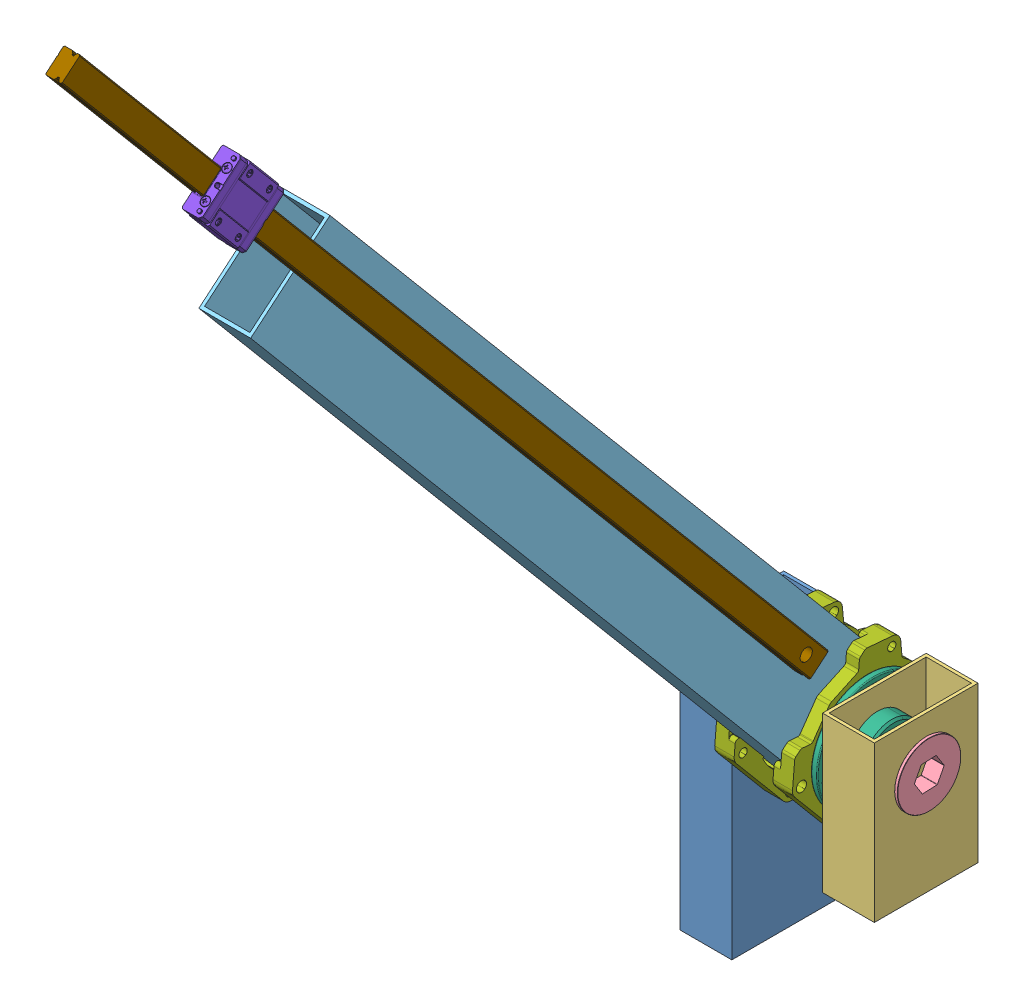
SolidWorks assembly Climber vsomething with rail, configuration Default. Lengths in mm.
Overall size (101.11 586.72 443.22).
12 component instances, 9 part files, 29 mates.
Components (placement in the parent):
- Climb Mount large-1: Climb Mount large [Default] at (52.6266 16.6141 118.8348) x (0 0 1) z (0 1 0) size (50.8 25.4 127)
- Climb axle-1: Climb axle [Default] at (124.4915 118.2141 118.8348) x (0 0.886216 -0.463271) z (-1 0 0) size (14.66 12.7 88.9)
- Climb Mount small-1: Climb Mount small [Default] at (122.4766 67.4141 118.8348) x (0 0 -1) z (0 1 0) size (50.8 25.4 76.2)
- am-2986 FR8ZZ Hex Bearing.step-1: am-2986 FR8ZZ Hex Bearing.step [Default] at (128.7732 118.2141 118.8348) x (0 0.886216 -0.463271) z (1 0 0) size (31.12 31.12 7.93)
- am-2986 FR8ZZ Hex Bearing.step-3: am-2986 FR8ZZ Hex Bearing.step [Default] at (46.3299 118.2141 118.8348) x (0 0 1) z (-1 0 0) size (31.12 31.12 7.93)
- Lower climb arm-1: Lower climb arm [Default] at (87.5516 99.754 101.3217) x (0 -0.643568 0.765389) z (-1 0 0) size (50.8 457.2 25.4)
- 1_2” Hex Bore Aluminum VersaHub (217-2592).step-1: 1_2” Hex Bore Aluminum VersaHub (217-2592).step [Default] at (55.8016 118.2141 118.8348) x (1 0 0) z (0 -0.643568 0.765389) size (12.7 55.88 55.88)
- 1_2” Hex Bore Aluminum VersaHub (217-2592).step-2: 1_2” Hex Bore Aluminum VersaHub (217-2592).step [Default] at (119.3016 118.2141 118.8348) x (-1 0 0) z (0 -0.341062 -0.940041) size (12.7 55.88 55.88)
- VersaBlock V2 (217-6111).step-1: VersaBlock V2 (217-6111).step [Default] at (71.6766 118.2141 118.8348) x (0 0.765389 0.643568) z (-1 0 0) size (61.04 66.67 9.53)
- VersaBlock V2 (217-6111).step-2: VersaBlock V2 (217-6111).step [Default] at (103.4266 118.2141 118.8348) x (0 -0.765389 -0.643568) z (1 0 0) size (61.04 66.67 9.53)
- 6709K115_Ball Bearing Carriage-1: 6709K115_Ball Bearing Carriage [6709K115] at (106.7516 504.278 431.2198) x (0 -0.643568 0.765389) z (0 0.765389 0.643568) size (27 10.16 34.7)
- 6709K173_Ball Bearing rail-1: 6709K173_Ball Bearing rail [6709K173] at (104.2516 381.3417 327.6783) x (0 0.643568 -0.765389) z (0 -0.765389 -0.643568) size (12 8.07 570)
Mates (geometry in assembly coordinates):
- Concentric1: concentric anti-aligned: cylinder of Climb Mount large-1 through (65.3266 118.2141 118.8348) axis (-1 0 0) radius 14.2875; cylinder of Climb Mount small-1 through (109.7766 118.2141 118.8348) axis (1 0 0) radius 14.2875
- Coincident1: coincident aligned: plane of Climb Mount large-1 through (52.6266 143.6141 118.8348) normal (0 1 0); plane of Climb Mount small-1 through (122.4766 143.6141 118.8348) normal (0 1 0)
- Coincident4: coincident anti-aligned: plane of Climb Mount small-1 through (135.1766 143.6141 93.4348) normal (1 0 0); plane of am-2986 FR8ZZ Hex Bearing.step-1 through (135.1766 130.5945 112.3629) normal (-1 0 0)
- Concentric3: concentric anti-aligned: cylinder of Climb Mount small-1 through (109.7766 118.2141 118.8348) axis (1 0 0) radius 14.2875; cylinder of am-2986 FR8ZZ Hex Bearing.step-1 through (136.7006 118.2141 118.8348) axis (-1 0 0) radius 14.2875
- Coincident6: coincident anti-aligned: plane of Climb Mount large-1 through (39.9266 143.6141 144.2348) normal (-1 0 0); plane of am-2986 FR8ZZ Hex Bearing.step-3 through (39.9266 118.2141 132.8048) normal (1 0 0)
- Concentric5: concentric anti-aligned: line of Climb Mount large-1 through (65.3266 118.2141 118.8348) axis (-1 0 0); axis of am-2986 FR8ZZ Hex Bearing.step-3 through (40.4346 118.2141 118.8348) axis (1 0 0)
- Coincident7: coincident anti-aligned: plane of Climb axle-1 through (35.5915 117.9068 126.1607) normal (0 0.463271 0.886216); plane of am-2986 FR8ZZ Hex Bearing.step-1 through (136.7006 117.9068 126.1607) normal (0 -0.463271 -0.886216)
- Coincident8: coincident anti-aligned: plane of Climb axle-1 through (35.5915 124.7121 115.4379) normal (0 0.53585 -0.844313); plane of am-2986 FR8ZZ Hex Bearing.step-1 through (136.7006 124.7121 115.4379) normal (0 -0.53585 0.844313)
- Coincident10: coincident anti-aligned: plane of Lower climb arm-1 through (74.8516 433.3431 415.0019) normal (-1 0 0); plane of VersaBlock V2 (217-6111).step-1 through (74.8516 118.2141 118.8348) normal (1 0 0)
- Coincident11: coincident anti-aligned: plane of Lower climb arm-1 through (74.8516 433.3431 415.0019) normal (0 -0.643568 0.765389); plane of VersaBlock V2 (217-6111).step-1 through (-4.6404 126.2065 156.7497) normal (0 0.643568 -0.765389)
- Coincident12: coincident anti-aligned: plane of Lower climb arm-1 through (74.8516 433.3431 415.0019) normal (0 -0.643568 0.765389); plane of VersaBlock V2 (217-6111).step-2 through (179.7436 79.49 117.4687) normal (0 0.643568 -0.765389)
- Coincident13: coincident anti-aligned: plane of Lower climb arm-1 through (100.2516 433.3431 415.0019) normal (1 0 0); plane of VersaBlock V2 (217-6111).step-2 through (100.2516 118.2141 118.8348) normal (-1 0 0)
- Parallel1: parallel anti-aligned: plane of Climb Mount small-1 through (109.7766 143.6141 93.4348) normal (-1 0 0); plane of Lower climb arm-1 through (100.2516 433.3431 415.0019) normal (1 0 0)
- Concentric6: concentric anti-aligned: cylinder of Lower climb arm-1 through (-356.9484 118.2141 118.8348) axis (1 0 0) radius 12.7; cylinder of VersaBlock V2 (217-6111).step-1 through (113.7106 118.2141 118.8348) axis (-1 0 0) radius 14.2748
- Concentric7: concentric aligned: cylinder of Lower climb arm-1 through (-356.9484 118.2141 118.8348) axis (1 0 0) radius 12.7; cylinder of VersaBlock V2 (217-6111).step-2 through (61.3926 118.2141 118.8348) axis (1 0 0) radius 14.2748
- Coincident16: coincident anti-aligned: plane of 1_2” Hex Bore Aluminum VersaHub (217-2592).step-2 through (106.6016 147.8694 108.0754) normal (-1 0 0); plane of VersaBlock V2 (217-6111).step-2 through (106.6016 114.0552 142.2813) normal (1 0 0)
- Concentric8: concentric anti-aligned: cylinder of 1_2” Hex Bore Aluminum VersaHub (217-2592).step-2 through (192.3949 99.9883 103.5098) axis (-1 0 0) radius 2.15; cylinder of VersaBlock V2 (217-6111).step-2 through (106.6016 99.9883 103.5098) axis (1 0 0) radius 2.4892
- Concentric9: concentric anti-aligned: cylinder of 1_2” Hex Bore Aluminum VersaHub (217-2592).step-2 through (192.3949 95.8294 126.9563) axis (-1 0 0) radius 2.15; cylinder of VersaBlock V2 (217-6111).step-2 through (106.6016 95.8294 126.9563) axis (1 0 0) radius 1.7272
- Coincident17: coincident anti-aligned: plane of 1_2” Hex Bore Aluminum VersaHub (217-2592).step-1 through (68.5016 142.3596 139.1373) normal (1 0 0); plane of VersaBlock V2 (217-6111).step-1 through (68.5016 95.8294 126.9563) normal (-1 0 0)
- Concentric10: concentric anti-aligned: cylinder of 1_2” Hex Bore Aluminum VersaHub (217-2592).step-1 through (-17.2918 99.9883 103.5098) axis (1 0 0) radius 2.15; cylinder of VersaBlock V2 (217-6111).step-1 through (68.5016 99.9883 103.5098) axis (-1 0 0) radius 2.4892
- Concentric11: concentric anti-aligned: cylinder of 1_2” Hex Bore Aluminum VersaHub (217-2592).step-1 through (-17.2918 95.8294 126.9563) axis (1 0 0) radius 2.15; cylinder of VersaBlock V2 (217-6111).step-1 through (68.5016 95.8294 126.9563) axis (-1 0 0) radius 1.7272
- Concentric12: concentric anti-aligned: cylinder of Climb Mount small-1 through (109.7766 118.2141 118.8348) axis (1 0 0) radius 14.2875; cylinder of 1_2” Hex Bore Aluminum VersaHub (217-2592).step-2 through (106.6016 118.2141 118.8348) axis (-1 0 0) radius 14.2949
- Coincident18: coincident anti-aligned: plane of Climb Mount small-1 through (109.7766 143.6141 93.4348) normal (-1 0 0); plane of 1_2” Hex Bore Aluminum VersaHub (217-2592).step-2 through (109.7766 131.6519 113.9593) normal (1 0 0)
- Coincident20: coincident anti-aligned: plane of Climb Mount large-1 through (65.3266 143.6141 144.2348) normal (1 0 0); plane of 1_2” Hex Bore Aluminum VersaHub (217-2592).step-1 through (65.3266 129.1552 128.0345) normal (-1 0 0)
- Coincident22: coincident anti-aligned: plane of 6709K115_Ball Bearing Carriage-1 through (108.2516 499.5132 420.0274) normal (-1 0 0); plane of 6709K173_Ball Bearing rail-1 through (108.2516 603.0171 506.8856) normal (1 0 0)
- Tangent1: tangent anti-aligned: cylinder of 6709K115_Ball Bearing Carriage-1 through (105.731 495.6123 417.6098) axis (0 0.765389 0.643568) radius 0.2084; plane of 6709K173_Ball Bearing rail-1 through (105.5254 602.3736 507.651) normal (0 0.643568 -0.765389)
- Coincident23: coincident anti-aligned: plane of Lower climb arm-1 through (100.2516 433.3431 415.0019) normal (1 0 0); plane of 6709K173_Ball Bearing rail-1 through (100.2516 595.9379 515.3049) normal (-1 0 0)
- Distance3: distance = 76.2 mm aligned: plane of 6709K173_Ball Bearing rail-1 through (105.7353 159.1514 149.0834) normal (0 -0.765389 -0.643568); plane of Lower climb arm-1 through (87.5516 99.754 101.3217) normal (0 -0.765389 -0.643568)
- Distance4: distance = 11.43 mm aligned: plane of 6709K173_Ball Bearing rail-1 through (100.7516 603.3389 506.5029) normal (0 0.643568 -0.765389); plane of Lower climb arm-1 through (74.8516 466.0364 376.1202) normal (0 0.643568 -0.765389)
